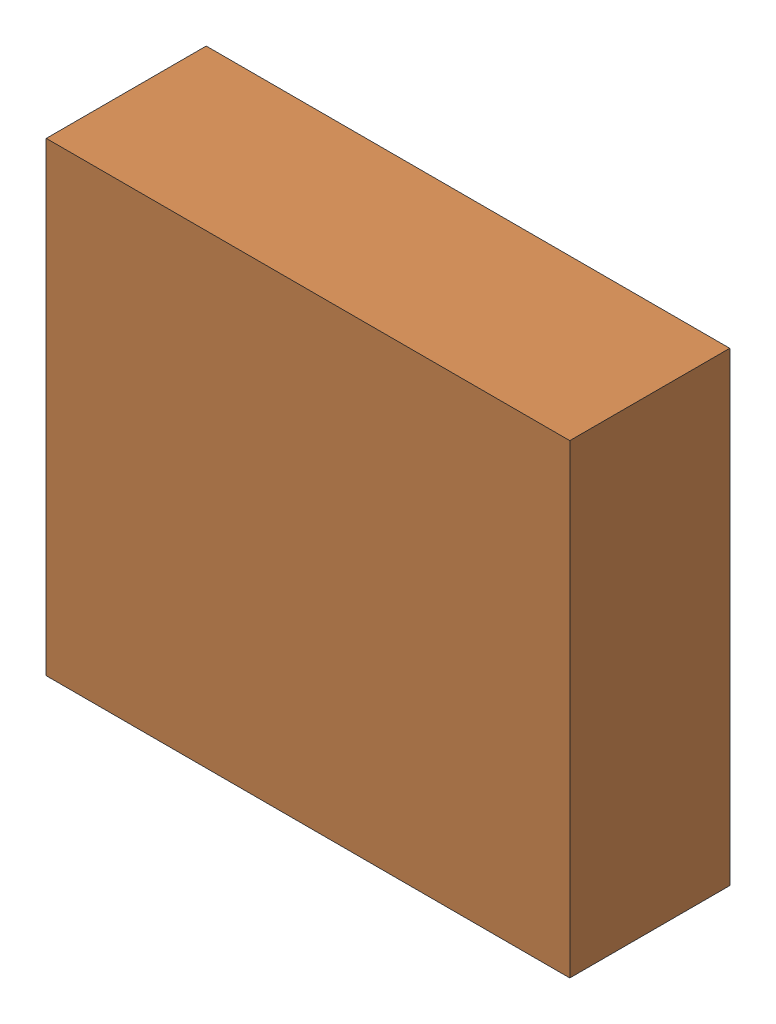
SolidWorks assembly U4, configuration Default. Lengths in mm.
Overall size (1.8 1.6 0.56).
4 component instances, 2 part files, 0 mates.
Components (placement in the parent):
- 1737316208-1: 1737316208 [Default] at (9.9248 45.3751 -2.194) x (-1 0 0) z (0 0 -1) size (0.3 0.3 0.01)
  - Cylinder-25-1: Cylinder-25 [Default] at origin size (0.3 0.3 0.01)
- 1088890552-1: 1088890552 [Default] at (9.35 45.85 -2.194) size (1.8 1.6 0.55)
  - Extruded-26-1: Extruded-26 [Default] at origin size (1.8 1.6 0.55)
